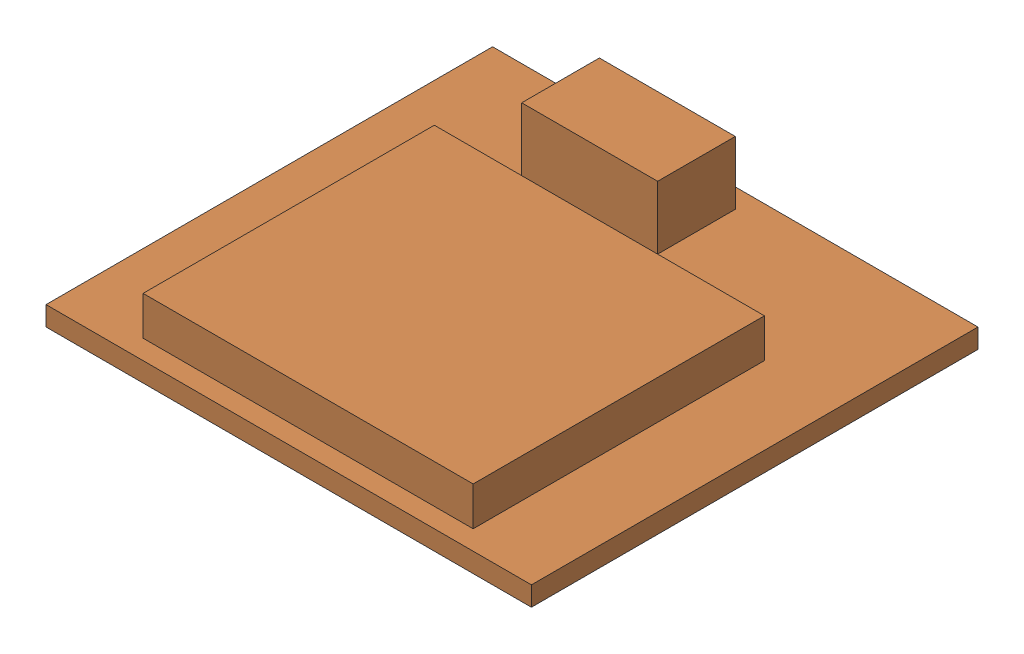
SolidWorks assembly SIM800L_ASM, configuration Default. Lengths in mm.
Overall size (25 5 23.96).
2 component instances, 2 part files, 0 mates.
Components (placement in the parent):
- SIM800L-1: SIM800L [Default] at (-1.3687 -1.5479 1.7738) size (25 5 23)
- SIM_CARD-1: SIM_CARD [Default] at (-2.6545 -2.1181 -3.1891) size (11 0.4 15)
